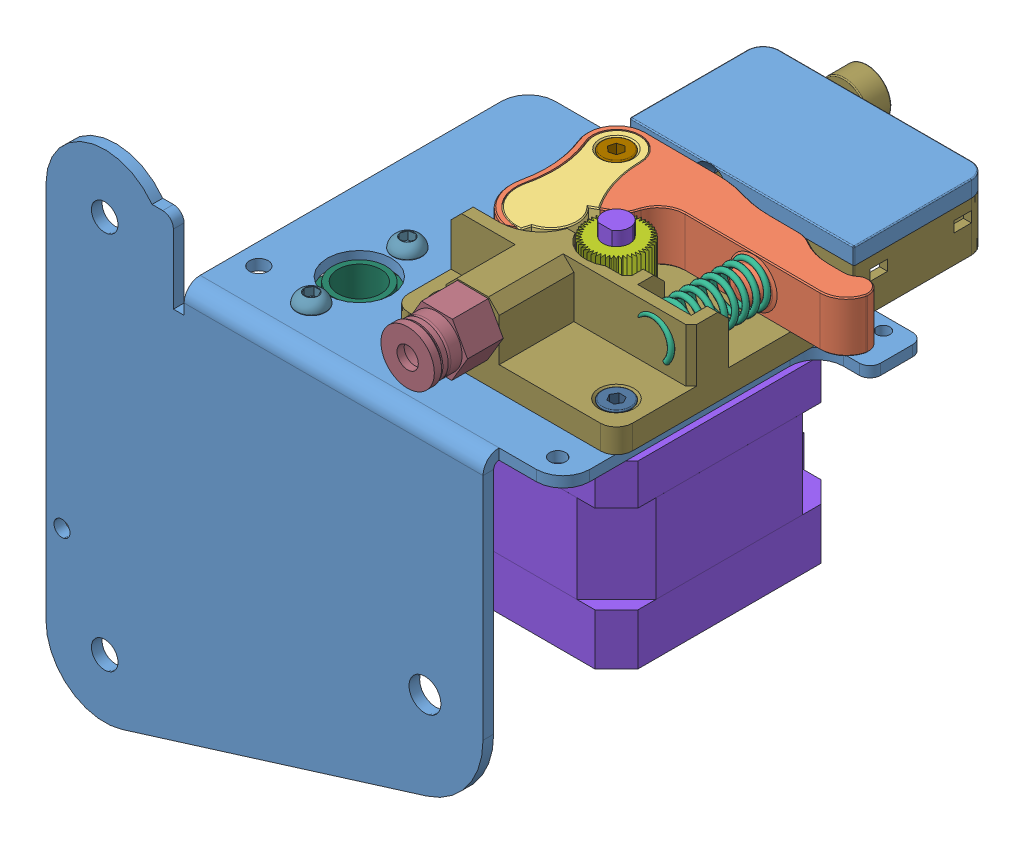
SolidWorks assembly 挤出器固定板左装配, configuration 默认. Lengths in mm.
Overall size (105.53 96.5 86.15).
25 component instances, 19 part files, 46 mates.
Components (placement in the parent):
- 一体挤出器固定板左_钣金-1: 一体挤出器固定板左_钣金 [默认] at (-55.4694 -7.0201 25.25) size (103.87 93 64.5)
- 手柄装配-1: 手柄装配 [Default] at (51.5662 -16.434 -29.5723) x (0.999984 0 0.005666) z (0 1 0) size (52.63 28.87 49.74)
  - 右挤出器手柄-1: 右挤出器手柄 [默认] at (-58.5845 -22.2423 40.7539) size (52.63 28.37 9.5)
  - 右挤出器盖板-1: 右挤出器盖板 [默认] at (-58.6245 -22.2423 41.2539) size (12.69 26.44 5.5)
  - U型轴承-1: U型轴承 [默认] at (-70.8245 -22.2423 48.5056) x (-0.923728 0.383049 0) z (0 0 1) size (12 12 4)
  - M3_8圆柱-1: M3_8圆柱 [默认] at (-70.8245 -22.2423 46.5056) x (-0.923728 0.383049 0) z (0 0 1) size (3 3 8)
- 1_8_25弹簧-1: 1_8_25弹簧 [Default] at (6.9047 34.2199 -4.8893) x (0.986352 0.16465 0) z (-0.16465 0.986352 0) size (8.42 22 8.42)
- 电机轴齿轮-1: 电机轴齿轮 [默认] at (-7.0953 28.9799 -7.75) x (0.005666 0 -0.999984) z (0 1 0) size (10.88 10.88 11.4)
- 42型步进电机-1: 42型步进电机 [Default] at (-7.0953 6.2299 -7.75) x (-1 0 0) z (0 0 -1) size (42.3 53.75 48.3)
- 内六角沉头螺栓M3_20-1: 内六角沉头螺栓M3_20 [内六角沉头螺栓M3_20] at (-22.5953 38.9799 -23.25) x (0.962664 0 -0.270699) z (0.270699 0 0.962664) size (5.6 20 5.6)
- 内六角沉头M3_10-4: 内六角沉头M3_10 [内六角沉头M3_10] at (8.4047 29.4799 -23.25) x (-0.213376 0 -0.97697) z (0.97697 0 -0.213376) size (5.6 10 5.6)
- 机米M3-2: 机米M3 [机米M3] at (-1.5954 31.7799 -7.7189) x (-0.999984 0 -0.005666) z (0 1 0) size (3 3 3)
- 远端挤出器料丝检测一体底座-1: 远端挤出器料丝检测一体底座 [默认] at (-7.0953 24.9799 -7.75) x (1 0 0) z (0 1 0) size (42 74 14.5)
- 内六角沉头M3_10-1: 内六角沉头M3_10 [内六角沉头M3_10] at (8.4047 29.4799 7.75) size (5.6 10 5.6)
- 内六角沉头M3_10-3: 内六角沉头M3_10 [内六角沉头M3_10] at (-22.5953 29.4799 7.75) size (5.6 10 5.6)
- 气动接头4-M6-1: 气动接头4-M6 [气动接头4-M8] at (-13.0653 34.2199 6.55) size (11.55 10.07 18.75)
- 圆头内六角M3_8-3: 圆头内六角M3_8 [圆头内六角M3_8] at (-39.9653 24.9799 16.55) size (5.49 10 5.49)
- 丝杆螺母-M24-1: 丝杆螺母-M24 [Default] at (-39.9653 22.1799 7.55) x (-1 0 0) z (0 0 1) size (12.8 10.7 24)
- 圆头内六角M3_8-2: 圆头内六角M3_8 [圆头内六角M3_8] at (-39.9653 24.9799 -1.45) x (0.982082 0 -0.188455) z (0.188455 0 0.982082) size (5.49 10 5.49)
- 弹性垫片M3-1: 弹性垫片M3 [弹性垫片M3] at (-39.9653 22.9799 -1.45) x (0 0 1) z (0 1 0) size (5 5 0.8)
- 弹性垫片M3-2: 弹性垫片M3 [弹性垫片M3] at (-39.9653 22.9799 16.55) x (0.188455 0 0.982082) z (0 1 0) size (5 5 0.8)
- M2.2x6自攻螺钉-1: M2.2x6自攻螺钉 [默认] at (-6.4653 34.2199 -51.4) x (0 -1 0) z (0 0 1) size (7.62 3.8 3.8)
- 料丝检测开关-新-1: 料丝检测开关-新 [默认] at (-6.4653 31.6199 -43.9) x (0 0 -1) z (1 0 0) size (20 15.45 17.4)
- M2.2x6自攻螺钉-2: M2.2x6自攻螺钉 [默认] at (-6.4653 34.2199 -36.4) x (0 -1 0) z (0.188455 0 0.982082) size (7.62 3.8 3.8)
- 远端挤出器料丝检测一体上盖-1: 远端挤出器料丝检测一体上盖 [默认] at (-7.0953 37.3199 -43.75) x (1 0 0) z (0 0 -1) size (42 6.45 25)
Mates (geometry in assembly coordinates):
- 重合42: coincident aligned: plane of 手柄装配-1/右挤出器盖板-1 through (-19.3831 38.9799 -7.7316) normal (0 1 0); plane of 内六角沉头螺栓M3_20-1 through (-19.7073 38.9799 -24.0621) normal (0 1 0)
- 同心62: concentric aligned: cylinder of 内六角沉头螺栓M3_20-1 through (-22.5953 18.9799 -23.25) axis (0 1 0) radius 1.5; cylinder of 手柄装配-1/右挤出器盖板-1 through (-22.5953 38.9799 -23.25) axis (0 1 0) radius 1.6
- 同心42: concentric aligned: cylinder of 电机轴齿轮-1 through (-7.0953 40.3799 -7.75) axis (0 -1 0) radius 2.5; cylinder of 42型步进电机-1 through (-7.0953 42.9799 -7.75) axis (0 -1 0) radius 2.5
- 距离1: distance = 4 mm anti-aligned: plane of 电机轴齿轮-1 through (-7.0953 28.9799 -7.75) normal (0 -1 0); plane of 42型步进电机-1 through (-7.0953 24.9799 -7.75) normal (0 1 0)
- 同心61: concentric anti-aligned: cylinder of 电机轴齿轮-1 through (-1.2375 31.7799 -7.7168) axis (-0.999984 0 -0.005666) radius 1.2; cylinder of 机米M3-2 through (13.1785 31.7799 -7.6352) axis (0.999984 0 0.005666) radius 1.5
- 相切1: tangent anti-aligned: cylinder of 电机轴齿轮-1 through (-7.0953 40.3799 -7.75) axis (0 -1 0) radius 2.5; plane of 机米M3-2 through (-4.5953 31.7799 -7.7359) normal (-0.999984 0 -0.005666)
- 重合45: coincident anti-aligned: plane of 一体挤出器固定板左_钣金-1 through (-50.0953 22.9799 -34.25) normal (0 -1 0); plane of 42型步进电机-1 through (14.0547 22.9799 13.4) normal (0 1 0)
- 同心67: concentric aligned: cylinder of 远端挤出器料丝检测一体底座-1 through (8.4047 29.4799 7.75) axis (0 -1 0) radius 1.5; cylinder of 一体挤出器固定板左_钣金-1 through (8.4047 24.9799 7.75) axis (0 -1 0) radius 1.6
- 重合46: coincident anti-aligned: plane of 一体挤出器固定板左_钣金-1 through (-50.0953 24.9799 -34.25) normal (0 1 0); plane of 远端挤出器料丝检测一体底座-1 through (10.9047 24.9799 10.25) normal (0 -1 0)
- 重合47: coincident aligned: plane of 内六角沉头M3_10-4 through (7.7646 29.4799 -26.1809) normal (0 1 0); plane of 远端挤出器料丝检测一体底座-1 through (10.9047 29.4799 10.25) normal (0 1 0)
- 重合48: coincident anti-aligned: plane of 手柄装配-1/右挤出器手柄-1 through (-19.3831 29.4799 -7.7316) normal (0 -1 0); plane of 远端挤出器料丝检测一体底座-1 through (10.9047 29.4799 10.25) normal (0 1 0)
- 平行3: parallel aligned: line of 手柄装配-1/右挤出器手柄-1 through (-13.0953 34.2299 -44.8104) axis (0 0 1); cylinder of 远端挤出器料丝检测一体底座-1 through (-13.0653 34.2199 17.4848) axis (0 0 1) radius 1.1
- 同心72: concentric anti-aligned: line of 1_8_25弹簧-1 through (6.9047 34.2199 12.683) axis (0 0 -1); cylinder of 远端挤出器料丝检测一体底座-1 through (6.9047 34.2199 15.6322) axis (0 0 1) radius 3
- 锁定2: lock: unknown of 1_8_25弹簧-1; unknown of 远端挤出器料丝检测一体底座-1
- 同心73: concentric aligned: cylinder of 远端挤出器料丝检测一体底座-1 through (8.4047 26.9799 -23.25) axis (0 -1 0) radius 3; cylinder of 一体挤出器固定板左_钣金-1 through (8.4047 24.9799 -23.25) axis (0 -1 0) radius 1.6
- 同心74: concentric anti-aligned: cylinder of 远端挤出器料丝检测一体底座-1 through (-22.5953 29.4799 7.75) axis (0 -1 0) radius 1.5; cylinder of 内六角沉头M3_10-3 through (-22.5953 19.4799 7.75) axis (0 1 0) radius 1.5
- 重合49: coincident aligned: plane of 远端挤出器料丝检测一体底座-1 through (10.9047 29.4799 10.25) normal (0 1 0); plane of 内六角沉头M3_10-3 through (-19.5953 29.4799 7.75) normal (0 1 0)
- 同心75: concentric anti-aligned: cylinder of 远端挤出器料丝检测一体底座-1 through (8.4047 29.4799 7.75) axis (0 -1 0) radius 1.5; cylinder of 内六角沉头M3_10-1 through (8.4047 19.4799 7.75) axis (0 1 0) radius 1.5
- 重合50: coincident aligned: plane of 远端挤出器料丝检测一体底座-1 through (10.9047 29.4799 10.25) normal (0 1 0); plane of 内六角沉头M3_10-1 through (11.4047 29.4799 7.75) normal (0 1 0)
- 重合51: coincident anti-aligned: plane of 远端挤出器料丝检测一体底座-1 through (-25.0953 29.4799 13.25) normal (0 0 1); plane of 气动接头4-M6-1 through (-13.0653 34.2199 13.25) normal (0 0 -1)
- 同心76: concentric anti-aligned: cylinder of 远端挤出器料丝检测一体底座-1 through (-13.0653 34.2199 13.25) axis (0 0 1) radius 2.5; cylinder of 气动接头4-M6-1 through (-13.0653 34.2199 13.25) axis (0 0 -1) radius 3
- 同心77: concentric anti-aligned: cylinder of 丝杆螺母-M24-1 through (-39.9653 13.4789 7.55) axis (0 1 0) radius 4; cylinder of 一体挤出器固定板左_钣金-1 through (-39.9653 24.9799 7.55) axis (0 -1 0) radius 6
- 平行4: parallel aligned: plane of 一体挤出器固定板左_钣金-1 through (-55.0953 24.9799 23.25) normal (-1 0 0); plane of 丝杆螺母-M24-1 through (-46.3653 18.4799 -2.6009) normal (-1 0 0)
- 同心78: concentric aligned: cylinder of 圆头内六角M3_8-3 through (-39.9653 16.9799 16.55) axis (0 1 0) radius 1.5; cylinder of 丝杆螺母-M24-1 through (-39.9653 22.1799 16.55) axis (0 1 0) radius 1.25
- 重合53: coincident anti-aligned: plane of 一体挤出器固定板左_钣金-1 through (-50.0953 24.9799 -34.25) normal (0 1 0); plane of 圆头内六角M3_8-3 through (-39.9653 24.9799 16.55) normal (0 -1 0)
- 同心81: concentric aligned: cylinder of 圆头内六角M3_8-2 through (-39.9653 16.9799 -1.45) axis (0 1 0) radius 1.5; cylinder of 丝杆螺母-M24-1 through (-39.9653 22.1799 -1.45) axis (0 1 0) radius 1.25
- 重合56: coincident anti-aligned: plane of 一体挤出器固定板左_钣金-1 through (-50.0953 24.9799 -34.25) normal (0 1 0); plane of 圆头内六角M3_8-2 through (-39.9653 24.9799 -1.45) normal (0 -1 0)
- 同心82: concentric anti-aligned: cylinder of 内六角沉头螺栓M3_20-1 through (-22.5953 18.9799 -23.25) axis (0 1 0) radius 1.5; cylinder of 远端挤出器料丝检测一体底座-1 through (-22.5953 29.4799 -23.25) axis (0 -1 0) radius 1.5
- 同心83: concentric anti-aligned: cylinder of 内六角沉头M3_10-4 through (8.4047 19.4799 -23.25) axis (0 1 0) radius 1.5; cylinder of 远端挤出器料丝检测一体底座-1 through (8.4047 26.9799 -23.25) axis (0 -1 0) radius 3
- 同心84: concentric aligned: cylinder of 一体挤出器固定板左_钣金-1 through (-7.0953 24.9799 -7.75) axis (0 -1 0) radius 11.5; cylinder of 42型步进电机-1 through (-7.0953 24.9799 -7.75) axis (0 -1 0) radius 11
- 同心85: concentric anti-aligned: cylinder of 一体挤出器固定板左_钣金-1 through (8.4047 24.9799 -23.25) axis (0 -1 0) radius 1.6; cylinder of 42型步进电机-1 through (8.4047 16.9799 -23.25) axis (0 1 0) radius 1.5
- 重合571: coincident anti-aligned: plane of 弹性垫片M3-1 through (-39.9653 22.9799 -1.45) normal (0 1 0); plane of 一体挤出器固定板左_钣金-1 through (-50.0953 22.9799 -34.25) normal (0 -1 0)
- 同心86: concentric aligned: cylinder of 丝杆螺母-M24-1 through (-39.9653 22.1799 -1.45) axis (0 1 0) radius 1.25; cylinder of 弹性垫片M3-1 through (-39.9653 22.1799 -1.45) axis (0 1 0) radius 2.5
- 重合58: coincident anti-aligned: plane of 一体挤出器固定板左_钣金-1 through (-50.0953 22.9799 -34.25) normal (0 -1 0); plane of 弹性垫片M3-2 through (-39.9653 22.9799 16.55) normal (0 1 0)
- 同心87: concentric aligned: cylinder of 丝杆螺母-M24-1 through (-39.9653 22.1799 16.55) axis (0 1 0) radius 1.25; cylinder of 弹性垫片M3-2 through (-39.9653 22.1799 16.55) axis (0 1 0) radius 2.5
- 重合59: coincident anti-aligned: plane of 丝杆螺母-M24-1 through (-39.9653 22.1799 7.55) normal (0 1 0); plane of 弹性垫片M3-2 through (-39.9653 22.1799 16.55) normal (0 -1 0)
- 重合572: coincident anti-aligned: plane of 远端挤出器料丝检测一体底座-1 through (-7.0953 31.6199 -7.75) normal (0 1 0); plane of 料丝检测开关-新-1 through (-6.4653 31.6199 -43.9) normal (0 -1 0)
- 同心88: concentric aligned: cylinder of 远端挤出器料丝检测一体底座-1 through (-6.4653 39.481 -51.4) axis (0 -1 0) radius 0.85; cylinder of 料丝检测开关-新-1 through (-6.4653 32.6199 -51.4) axis (0 -1 0) radius 1.25
- 同心89: concentric aligned: cylinder of 远端挤出器料丝检测一体底座-1 through (-6.4653 39.481 -36.4) axis (0 -1 0) radius 0.85; cylinder of 料丝检测开关-新-1 through (-6.4653 32.6199 -36.4) axis (0 -1 0) radius 1.25
- 重合573: coincident anti-aligned: plane of M2.2x6自攻螺钉-1 through (-4.5653 32.6199 -51.4) normal (0 -1 0); plane of 料丝检测开关-新-1 through (-6.4653 32.6199 -43.9) normal (0 1 0)
- 同心90: concentric anti-aligned: cylinder of M2.2x6自攻螺钉-1 through (-6.4653 41.1965 -51.4) axis (0 1 0) radius 1.1; cylinder of 料丝检测开关-新-1 through (-6.4653 32.6199 -51.4) axis (0 -1 0) radius 1.25
- 重合574: coincident anti-aligned: plane of 料丝检测开关-新-1 through (-6.4653 32.6199 -43.9) normal (0 1 0); plane of M2.2x6自攻螺钉-2 through (-4.5993 32.6199 -36.7581) normal (0 -1 0)
- 同心91: concentric anti-aligned: cylinder of 料丝检测开关-新-1 through (-6.4653 32.6199 -36.4) axis (0 -1 0) radius 1.25; cylinder of M2.2x6自攻螺钉-2 through (-6.4653 41.1965 -36.4) axis (0 1 0) radius 1.1
- 重合575: coincident anti-aligned: plane of 远端挤出器料丝检测一体底座-1 through (10.9047 34.2199 -53.25) normal (0 1 0); plane of 远端挤出器料丝检测一体上盖-1 through (-7.0953 34.2199 -43.75) normal (0 -1 0)
- 重合576: coincident aligned: plane of 远端挤出器料丝检测一体底座-1 through (-25.0953 29.4799 -56.25) normal (0 0 -1); plane of 远端挤出器料丝检测一体上盖-1 through (13.9047 34.2199 -56.25) normal (0 0 -1)
- 重合577: coincident aligned: plane of 远端挤出器料丝检测一体底座-1 through (13.9047 29.4799 -53.25) normal (1 0 0); plane of 远端挤出器料丝检测一体上盖-1 through (13.9047 34.2199 -31.25) normal (1 0 0)
